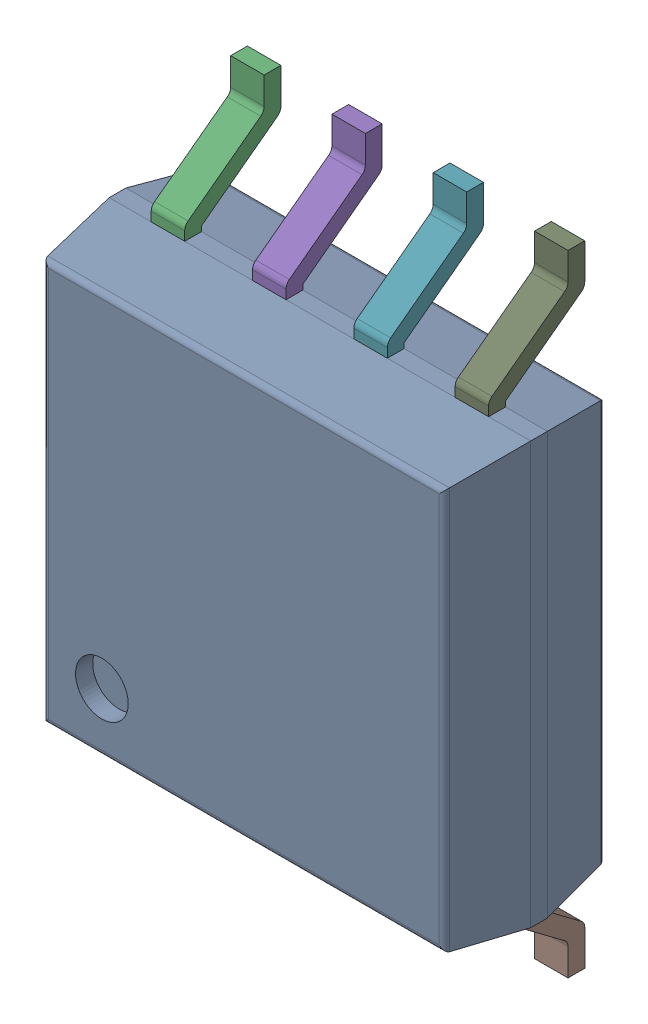
SolidWorks assembly IC55_1.step, configuration Default. Lengths in mm.
Overall size (5.29 7.9 2.16).
3 component instances, 2 part files, 0 mates.
Components (placement in the parent):
- 6348792448_1.step-3: 6348792448_1.step [Default] at (434.166 277.338 0) x (0 1 0) z (0 0 1) size (7.9 5.29 2.16)
  - Body-12_1.step-5: Body-12_1.step [Default] at origin size (5.29 5.29 2.01)
  - PinsArrayLR-13_1.step-5: PinsArrayLR-13_1.step [Default] at origin size (7.9 4.23 1.21)
